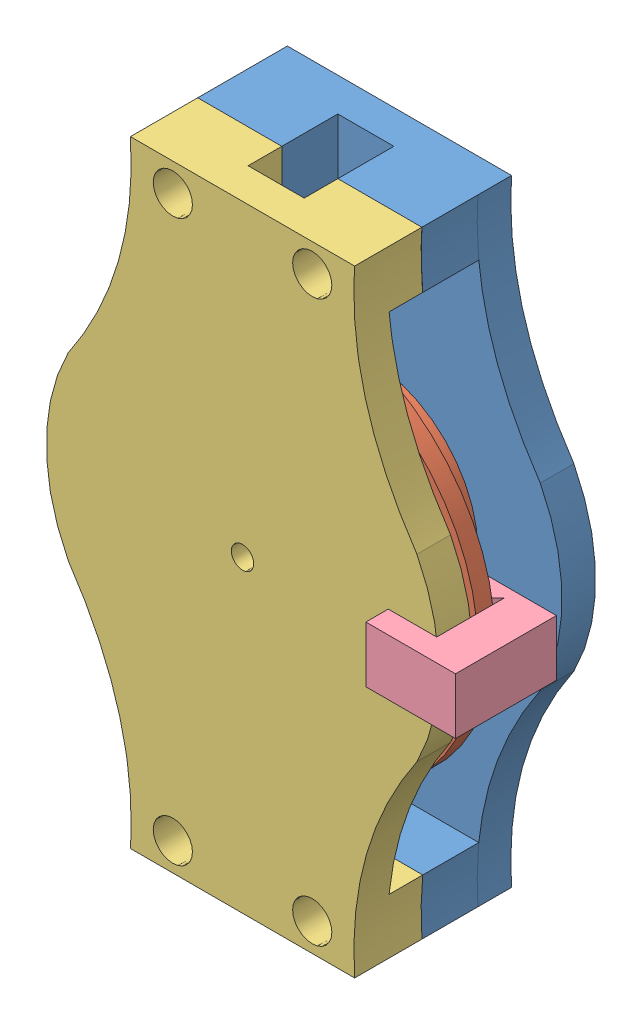
SolidWorks assembly Assem1, configuration Default. Lengths in mm.
Overall size (38.5 55 16).
4 component instances, 4 part files, 16 mates.
Components (placement in the parent):
- Part1-1: Part1 [Default] at origin size (35 55 11)
- Part4-1: Part4 [Default] at (0 0 3) size (35 35 7.5)
- Part5-1: Part5 [Default] at (0 0 11) size (35 55 6)
- brake-1: brake [Default] at (0 0 9) x (-1 0 0) z (0 0 -1) size (8 5 9)
Mates (geometry in assembly coordinates):
- InPlace1: in place: plane of Part1-1 through (0 0 0) normal (0 0 1); moOrthogonalPlaneRef_w of Part1-1 through (0 0 0) normal (0 1 0); plane of Part1-1 through (0 0 0) normal (1 0 0); unknown of Part1-1
- Coincident1: coincident aligned: plane of Part1-1; plane of assembly
- Coincident2: coincident aligned: plane of Part1-1 through (0 0 0) normal (0 1 0); moOrthogonalPlaneRef_w of assembly
- Coincident3: coincident anti-aligned: plane of Part1-1 through (0 0 0) normal (1 0 0); moOrthogonalPlaneRef_w of assembly
- InPlace4: in place: plane of Part1-1 through (0 0 3) normal (0 0 1); plane of Part4-1 through (0 0 3) normal (0 0 1); plane of Part1-1 through (0 0 3) normal (0 0 1); plane of Part4-1 through (0 0 3) normal (0 1 0); plane of Part1-1 through (0 0 3) normal (0 0 1); plane of Part4-1 through (0 0 3) normal (1 0 0); plane of Part1-1 through (0 0 3) normal (0 0 1); unknown of Part4-1
- Coincident10: coincident aligned: plane of Part1-1; plane of Part4-1
- Coincident11: coincident aligned: moOrthogonalPlaneRef_w of Part1-1 through (0 0 3) normal (0 1 0); plane of Part4-1 through (0 0 3) normal (0 1 0)
- Coincident12: coincident anti-aligned: moOrthogonalPlaneRef_w of Part1-1 through (0 0 3) normal (-1 0 0); plane of Part4-1 through (0 0 3) normal (1 0 0)
- InPlace5: in place: plane of Part1-1 through (0 0 11) normal (0 0 1); plane of Part5-1 through (0 0 11) normal (0 0 1); plane of Part1-1 through (0 0 11) normal (0 0 1); plane of Part5-1 through (0 0 11) normal (0 1 0); plane of Part1-1 through (0 0 11) normal (0 0 1); plane of Part5-1 through (0 0 11) normal (1 0 0); plane of Part1-1 through (0 0 11) normal (0 0 1); unknown of Part5-1
- Coincident13: coincident aligned: plane of Part1-1; plane of Part5-1
- Coincident14: coincident aligned: moOrthogonalPlaneRef_w of Part1-1 through (0 0 11) normal (0 1 0); plane of Part5-1 through (0 0 11) normal (0 1 0)
- Coincident15: coincident anti-aligned: moOrthogonalPlaneRef_w of Part1-1 through (0 0 11) normal (-1 0 0); plane of Part5-1 through (0 0 11) normal (1 0 0)
- InPlace6: in place: plane of Part4-1 through (0 0 9) normal (0 0 -1); plane of brake-1 through (0 0 9) normal (0 0 -1); plane of Part4-1 through (0 0 9) normal (0 0 -1); unknown of brake-1; plane of Part4-1 through (0 0 9) normal (0 0 -1); plane of brake-1 through (0 0 9) normal (-1 0 0); plane of Part4-1 through (0 0 9) normal (0 0 -1); unknown of brake-1
- Coincident1: coincident aligned: plane of Part4-1; plane of brake-1
- Coincident2: coincident aligned: moOrthogonalPlaneRef_w of Part4-1 through (0 0 9) normal (0 1 0); plane of brake-1
- Coincident3: coincident anti-aligned: moOrthogonalPlaneRef_w of Part4-1 through (0 0 9) normal (1 0 0); plane of brake-1 through (0 0 9) normal (-1 0 0)
